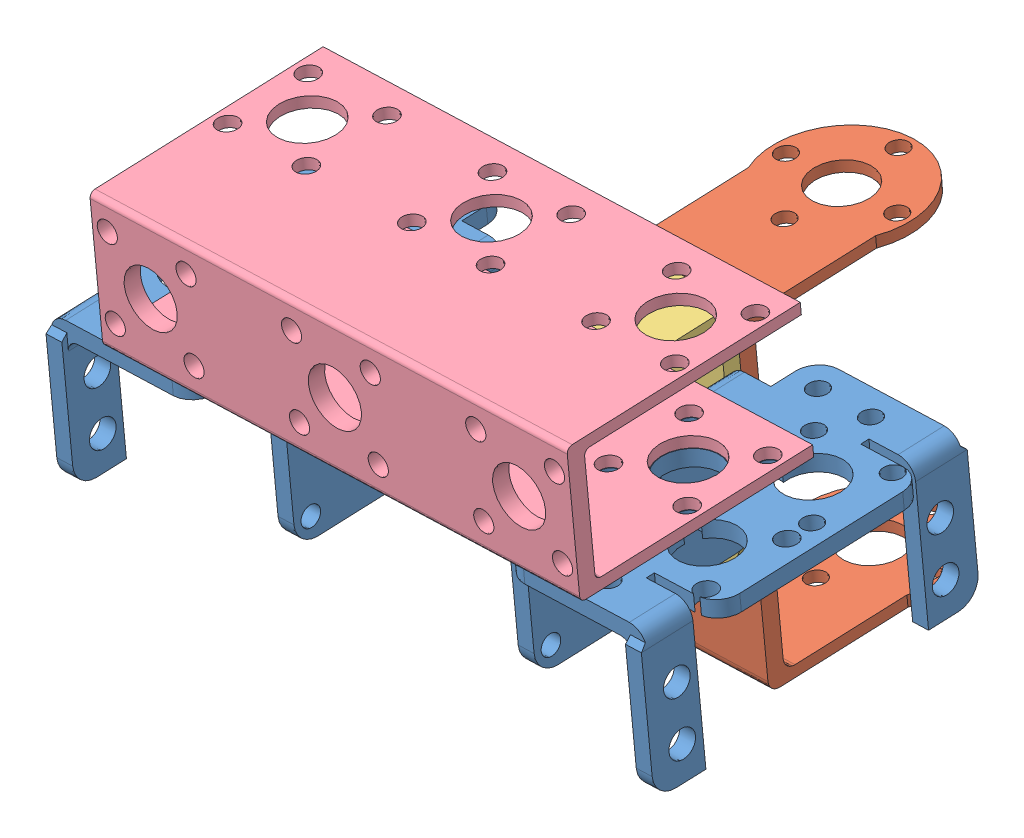
SolidWorks assembly thorax, configuration Predeterminado. Lengths in mm.
Overall size (121.13 89.74 110.01).
5 component instances, 4 part files, 12 mates.
Components (placement in the parent):
- multi_purpose_bracket-5: multi_purpose_bracket [Predeterminado] at (-36.1128 7.062 -141.3114) x (0.010773 0.051466 -0.998617) z (-0.998723 -0.048749 -0.013287) size (60 27 38.5)
- multi_purpose_bracket-6: multi_purpose_bracket [Predeterminado] at (35.5955 10.5622 -140.3575) x (-0.010773 -0.051466 0.998617) z (0.998723 0.048749 0.013287) size (60 27 38.5)
- u_bracket-1: u_bracket [Predeterminado] at (1.755 -22.5164 -174.0711) x (-0.0495 0.997478 0.050873) z (-0.998716 -0.048884 -0.013293) size (60 44.22 26.36)
- l_shaped-1: l_shaped [Predeterminado] at (2.7358 -16.0886 -169.7237) x (0.998723 0.048749 0.013287) z (-0.049366 0.997484 0.050875) size (26.4 43.78 46.22)
- channel_bracket-1: channel_bracket [Predeterminado] at (-1.1997 19.7326 -110.1601) x (0.998723 0.048749 0.013287) z (-0.049366 0.997484 0.050875) size (90 43 25)
Mates (geometry in assembly coordinates):
- Concéntrica4: concentric aligned: cylinder of u_bracket-1 through (2.2206 -20.2919 -217.2323) axis (-0.010773 -0.051466 0.998617) radius 5.4; cylinder of l_shaped-1 through (1.7442 -22.5678 -173.0725) axis (-0.010773 -0.051466 0.998617) radius 5.3
- Coincidente5: coincident anti-aligned: plane of u_bracket-1 through (1.7442 -22.5678 -173.0725) normal (-0.010773 -0.051466 0.998617); plane of l_shaped-1 through (1.7442 -22.5678 -173.0725) normal (0.010773 0.051466 -0.998617)
- Concéntrica6: concentric aligned: cylinder of u_bracket-1 through (-5.5611 -13.248 -216.9532) axis (-0.010773 -0.051466 0.998617) radius 1.8; cylinder of l_shaped-1 through (-6.0375 -15.5238 -172.7934) axis (-0.010773 -0.051466 0.998617) radius 1.5114
- Concéntrica7: concentric anti-aligned: circle of l_shaped-1; circle of channel_bracket-1
- Coincidente6: coincident anti-aligned: plane of l_shaped-1 through (-0.2586 8.8121 -140.8344) normal (-0.049366 0.997484 0.050875); plane of channel_bracket-1 through (-45.4929 5.2247 -114.3898) normal (0.049366 -0.997484 -0.050875)
- Concéntrica8: concentric aligned: circle of multi_purpose_bracket-5; circle of channel_bracket-1
- Concéntrica9: concentric aligned: circle of multi_purpose_bracket-6; circle of channel_bracket-1
- Concéntrica10: concentric anti-aligned: cylinder of multi_purpose_bracket-5 through (-27.3822 2.1105 -134.0375) axis (-0.049366 0.997484 0.050875) radius 1.8; cylinder of channel_bracket-1 through (-28.8632 32.035 -132.5113) axis (0.049366 -0.997484 -0.050875) radius 1.9
- Concéntrica11: concentric anti-aligned: cylinder of multi_purpose_bracket-6 through (27.1987 4.7747 -133.3114) axis (-0.049366 0.997484 0.050875) radius 1.8; cylinder of channel_bracket-1 through (25.7177 34.6992 -131.7852) axis (0.049366 -0.997484 -0.050875) radius 1.9
- Concéntrica12: concentric aligned: cylinder of l_shaped-1 through (-7.7537 8.0681 -133.5187) axis (0.049366 -0.997484 -0.050875) radius 1.8; cylinder of channel_bracket-1 through (-8.9879 33.0052 -132.2469) axis (0.049366 -0.997484 -0.050875) radius 1.9
- Coincidente8: coincident anti-aligned: plane of multi_purpose_bracket-5 through (-36.1128 7.062 -141.3114) normal (-0.049366 0.997484 0.050875); plane of channel_bracket-1 through (-45.4929 5.2247 -114.3898) normal (0.049366 -0.997484 -0.050875)
- Coincidente9: coincident anti-aligned: plane of multi_purpose_bracket-6 through (35.5955 10.5622 -140.3575) normal (-0.049366 0.997484 0.050875); plane of channel_bracket-1 through (-45.4929 5.2247 -114.3898) normal (0.049366 -0.997484 -0.050875)
